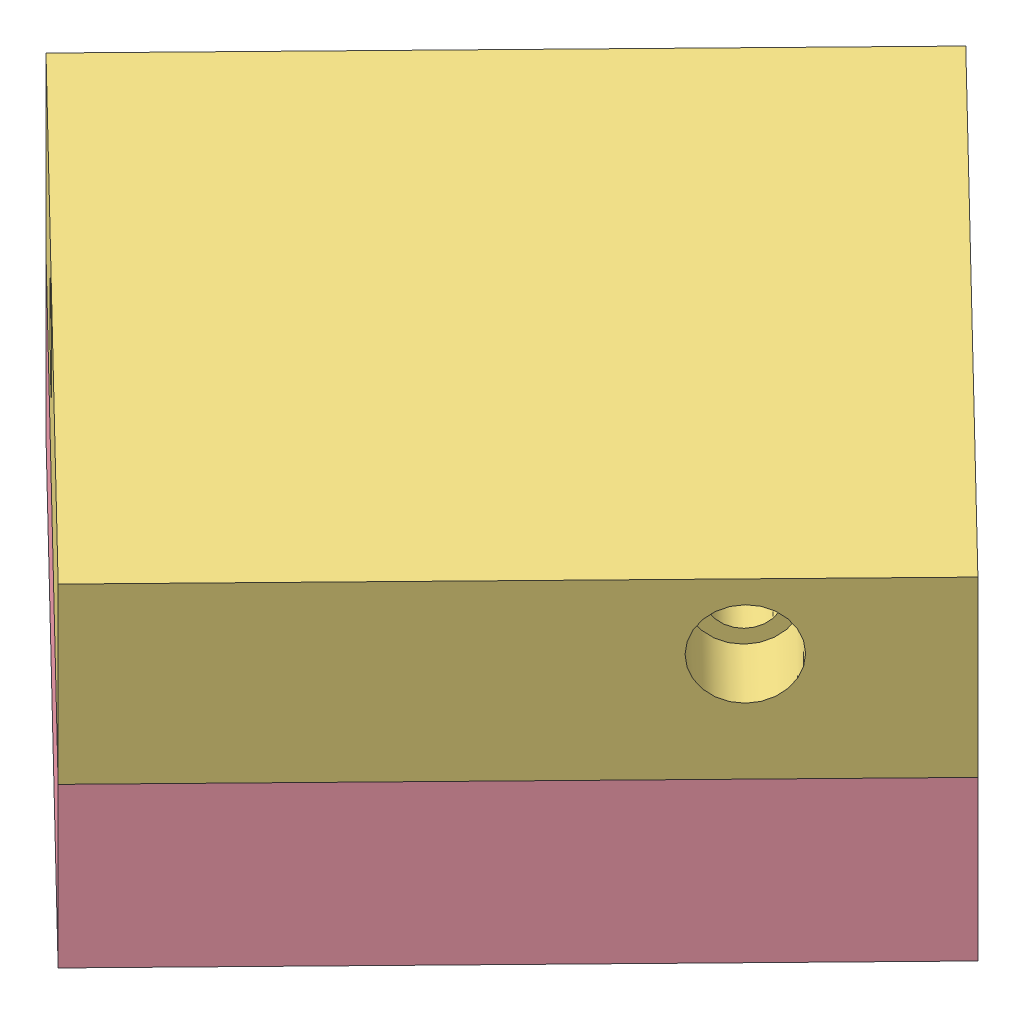
SolidWorks assembly AlphaSenseAssembly, configuration Default. Lengths in mm.
Overall size (127.28 46 127.28).
6 component instances, 4 part files, 16 mates.
Components (placement in the parent):
- Alphasense-1: Alphasense [Default] at origin size (32.33 16.5 32.33)
- Alphasense-2: Alphasense [Default] at (27.0859 0 26.3765) size (32.33 16.5 32.33)
- Alphasense-3: Alphasense [Default] at (-9.2998 0 36.6454) x (-0.443946 0 -0.896053) z (0.896053 0 -0.443946) size (32.33 16.5 32.33)
- AlphasenseBoard-1: AlphasenseBoard [Default] at (5.9287 -3.65 21.0073) x (0.716426 0 0.697663) z (-0.697663 0 0.716426) size (77.81 5.65 72.74)
- baseAlpha-1: baseAlpha [Default] at (5.9276 13.5 21.0094) x (0.716375 0 0.697716) z (0.697716 0 -0.716375) size (90.01 24 90)
- topAlpha-1: topAlpha [Default] at (3.8206 8.5 -41.319) x (0.716375 0 0.697716) z (0.697716 0 -0.716375) size (90 22 90.01)
Mates (geometry in assembly coordinates):
- Parallel1: parallel aligned: plane of Alphasense-1 through (0 13.5 0) normal (0 1 0); plane of Alphasense-2 through (27.0859 13.5 26.3765) normal (0 1 0)
- Parallel2: parallel aligned: plane of Alphasense-1 through (0 13.5 0) normal (0 1 0); plane of Alphasense-2 through (27.0859 13.5 26.3765) normal (0 1 0)
- Coincident1: coincident aligned: plane of Alphasense-1 through (0 13.5 0) normal (0 1 0); plane of Alphasense-2 through (27.0859 13.5 26.3765) normal (0 1 0)
- Coincident2: coincident aligned: plane of Alphasense-1 through (0 13.5 0) normal (0 1 0); plane of Alphasense-3 through (-9.2998 13.5 36.6454) normal (0 1 0)
- Coincident4: coincident anti-aligned: plane of Alphasense-1 through (0 -2 0) normal (0 -1 0); plane of AlphasenseBoard-1 through (0 -2 0) normal (0 1 0)
- Concentric1: concentric aligned: cylinder of Alphasense-1 through (0 13.5 0) axis (0 -1 0) radius 16.1655; cylinder of AlphasenseBoard-1 through (0 -2 0) axis (0 -1 0) radius 2
- Concentric2: concentric aligned: cylinder of Alphasense-2 through (27.0859 13.5 26.3765) axis (0 -1 0) radius 16.1655; cylinder of AlphasenseBoard-1 through (27.0859 -2 26.3765) axis (0 -1 0) radius 2
- Concentric3: concentric aligned: cylinder of Alphasense-3 through (-9.2998 13.5 36.6454) axis (0 -1 0) radius 16.1655; cylinder of AlphasenseBoard-1 through (-9.2998 -2 36.6454) axis (0 -1 0) radius 2
- Coincident5: coincident anti-aligned: plane of Alphasense-1 through (0 13.5 0) normal (0 1 0); plane of baseAlpha-1 through (-11.9396 13.5 18.2751) normal (0 -1 0)
- Concentric5: concentric anti-aligned: cylinder of Alphasense-1 through (0 13.5 0) axis (0 -1 0) radius 16.1655; cylinder of baseAlpha-1 through (0 8.5 0) axis (0 1 0) radius 16.2
- Coincident6: coincident anti-aligned: plane of Alphasense-2 through (27.0859 13.5 26.3765) normal (0 1 0); plane of baseAlpha-1 through (5.9276 13.5 21.0094) normal (0 -1 0)
- Parallel3: parallel anti-aligned: plane of AlphasenseBoard-1 through (0 -3.65 0) normal (0 -1 0); plane of topAlpha-1 through (27.0855 -7.75 26.3781) normal (0 1 0)
- Coincident7: coincident aligned: plane of baseAlpha-1 through (-58.9851 8.5 23.1577) normal (-0.697716 0 0.716375); plane of topAlpha-1 through (-58.9808 -13.5 23.1618) normal (-0.697716 0 0.716375)
- Coincident8: coincident aligned: plane of baseAlpha-1 through (5.4929 8.5 85.9563) normal (0.716375 0 0.697716); plane of topAlpha-1 through (68.2943 -13.5 21.4754) normal (0.716375 0 0.697716)
- Concentric8: concentric aligned: cylinder of AlphasenseBoard-1 through (-16.514 -2 13.6112) axis (0 -1 0) radius 1.4; cylinder of baseAlpha-1 through (-16.5145 14.5 13.6117) axis (0 -1 0) radius 1.4
- Coincident9: coincident anti-aligned: plane of baseAlpha-1 through (5.9276 8.5 21.0094) normal (0 -1 0); plane of topAlpha-1 through (3.8206 8.5 -41.319) normal (0 1 0)
